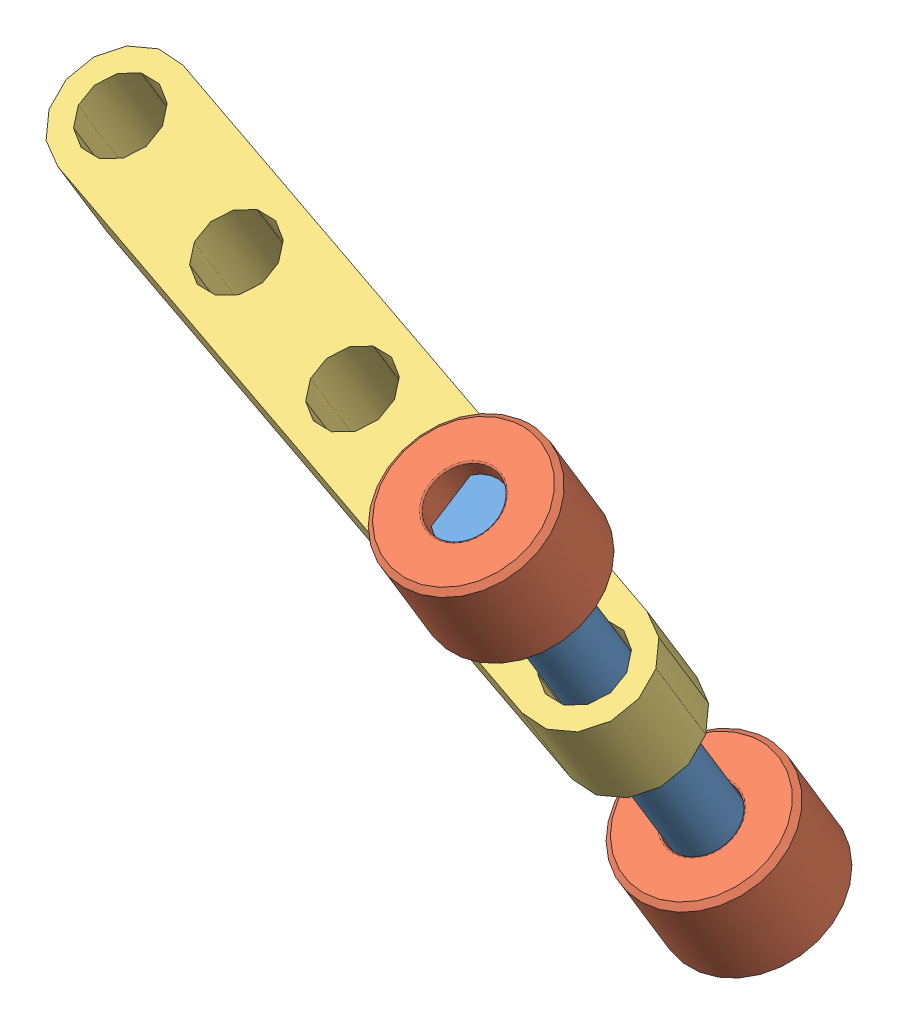
SolidWorks assembly Link Assembly - Upper Link Removed, configuration Default. Lengths in mm.
Overall size (35.69 26.34 20.92).
4 component instances, 3 part files, 28 mates.
Components (placement in the parent):
- Link D Shaft-1: Link D Shaft [Default] at (204.6422 -7.107 -10.2105) x (0 -0.854612 -0.519267) z (-0.011532 0.519233 -0.854555) size (25 2.4 2.9)
- 6056N11_Carbon Steel Set Screw Collar-5: 6056N11_Carbon Steel Set Screw Collar [6056N11] at (204.6422 -18.4789 -17.1202) x (-0.011532 0.519233 -0.854555) z (0 0.854612 0.519267) size (7 7.1 5)
- 6056N11_Carbon Steel Set Screw Collar-6: 6056N11_Carbon Steel Set Screw Collar [6056N11] at (204.6422 -0.0921 -5.9483) x (-0.011532 0.519233 -0.854555) z (0 0.854612 0.519267) size (7 7.1 5)
- Base Link-1: Base Link [Default] at (190.2189 -4.9679 -13.7311) x (-0.96155 0.142607 -0.234702) z (0 -0.854612 -0.519267) size (35.35 5.35 4.5)
Mates (geometry in assembly coordinates):
- Concentric30: concentric aligned: cylinder of Base Link v2-1 through (210.3071 -3.521 -6.1819) axis (0 -0.854612 -0.519267) radius 1.675; cylinder of Upper Link-1 through (199.4791 31.9793 -36.1428) axis (0 -0.854612 -0.519267) radius 1.51
- Coincident32: coincident aligned: plane of Base Link v2-1 through (196.7784 -8.808 -1.8135) normal (0 0.854612 0.519267); plane of Upper Link-1 through (206.0825 22.3111 -33.2299) normal (0 0.854612 0.519267)
- Coincident134: coincident aligned: plane of Base Link v2-1 through (196.7784 -8.808 -1.8135) normal (0 0.854612 0.519267); plane of Aluminum D Shaft-2 through (235.3041 1.5645 -21.6739) normal (0 0.854612 0.519267)
- Concentric78: concentric anti-aligned: cylinder of Aluminum D Shaft-2 through (235.3041 -5.2724 -25.828) axis (0 0.854612 0.519267) radius 1.45; cylinder of 6056N11_Carbon Steel Set Screw Collar-4 through (235.3041 18.9756 -11.0948) axis (0 -0.854612 -0.519267) radius 1.5
- Concentric79: concentric anti-aligned: cylinder of Aluminum D Shaft-2 through (235.3041 -5.2724 -25.828) axis (0 0.854612 0.519267) radius 1.45; cylinder of 6056N11_Carbon Steel Set Screw Collar-3 through (235.3041 7.9191 -17.8128) axis (0 -0.854612 -0.519267) radius 1.5
- Parallel31: parallel aligned: plane of Aluminum D Shaft-2 through (235.6236 -5.737 -25.0634) normal (0.336281 -0.489026 0.804841); plane of 6056N11_Carbon Steel Set Screw Collar-3 through (236.4811 4.0709 -16.294) normal (0.336281 -0.489026 0.804841)
- Parallel32: parallel aligned: plane of Aluminum D Shaft-2 through (235.6236 -5.737 -25.0634) normal (0.336281 -0.489026 0.804841); plane of 6056N11_Carbon Steel Set Screw Collar-4 through (236.4811 15.1275 -9.576) normal (0.336281 -0.489026 0.804841)
- Coincident178: coincident anti-aligned: plane of Upper Link-1 through (206.0825 22.3111 -33.2299) normal (0 0.854612 0.519267); plane of Link D Shaft-1 through (204.6422 -7.107 -10.2105) normal (0 -0.854612 -0.519267)
- Concentric113: concentric anti-aligned: cylinder of Upper Link-1 through (199.4791 20.4421 -43.1529) axis (0 0.854612 0.519267) radius 1.51; cylinder of Link D Shaft-1 through (204.6422 3.5757 -3.7197) axis (0 -0.854612 -0.519267) radius 1.45
- Concentric114: concentric aligned: cylinder of Link D Shaft-1 through (204.6422 3.5757 -3.7197) axis (0 -0.854612 -0.519267) radius 1.45; cylinder of 6056N11_Carbon Steel Set Screw Collar-5 through (204.6422 -14.2059 -14.5239) axis (0 -0.854612 -0.519267) radius 1.5
- Parallel33: parallel aligned: plane of Link D Shaft-1 through (203.6922 3.57 -3.7103) normal (-0.999934 -0.005988 0.009855); plane of 6056N11_Carbon Steel Set Screw Collar-5 through (201.1424 -16.3634 -15.7875) normal (-0.999934 -0.005988 0.009855)
- Concentric115: concentric aligned: cylinder of Link D Shaft-1 through (204.6422 3.5757 -3.7197) axis (0 -0.854612 -0.519267) radius 1.45; cylinder of 6056N11_Carbon Steel Set Screw Collar-6 through (204.6422 4.1809 -3.3519) axis (0 -0.854612 -0.519267) radius 1.5
- Parallel34: parallel aligned: plane of Link D Shaft-1 through (203.6922 3.57 -3.7103) normal (-0.999934 -0.005988 0.009855); plane of 6056N11_Carbon Steel Set Screw Collar-6 through (201.1424 2.0234 -4.6156) normal (-0.999934 -0.005988 0.009855)
- Coincident179: coincident anti-aligned: plane of Upper Link-1 through (206.0825 16.5425 -36.735) normal (0 -0.854612 -0.519267); plane of 6056N11_Carbon Steel Set Screw Collar-5 through (204.6422 -14.2059 -14.5239) normal (0 0.854612 0.519267)
- Coincident181: coincident anti-aligned: plane of Upper Link-1 through (206.0825 28.0798 -29.7249) normal (0 0.854612 0.519267); plane of 6056N11_Carbon Steel Set Screw Collar-6 through (204.6422 -0.0921 -5.9483) normal (0 -0.854612 -0.519267)
- Concentric130: concentric anti-aligned: cylinder of Link D Shaft-1 through (204.6422 3.5757 -3.7197) axis (0 -0.854612 -0.519267) radius 1.45; cylinder of Upper Link-2 through (214.1317 -11.1072 -13.8178) axis (0 0.854612 0.519267) radius 1.675
- Concentric131: concentric anti-aligned: cylinder of Aluminum D Shaft-2 through (235.3041 -5.2724 -25.828) axis (0 0.854612 0.519267) radius 1.45; cylinder of Upper Link-2 through (235.3041 3.4874 -20.5055) axis (0 -0.854612 -0.519267) radius 1.675
- Concentric132: concentric anti-aligned: cylinder of Base Link v2-1 through (210.3071 -3.521 -6.1819) axis (0 -0.854612 -0.519267) radius 1.675; cylinder of Upper Link-2 through (214.1317 -11.1072 -13.8178) axis (0 0.854612 0.519267) radius 1.675
- Coincident204: coincident anti-aligned: plane of 6056N11_Carbon Steel Set Screw Collar-5 through (204.6422 -14.2059 -14.5239) normal (0 0.854612 0.519267); plane of Upper Link-2 through (226.8352 -6.9654 -20.6345) normal (0 -0.854612 -0.519267)
- Coincident205: coincident anti-aligned: plane of 6056N11_Carbon Steel Set Screw Collar-6 through (204.6422 -0.0921 -5.9483) normal (0 -0.854612 -0.519267); plane of Upper Link-2 through (226.8352 4.5719 -13.6244) normal (0 0.854612 0.519267)
- Coincident206: coincident anti-aligned: plane of Link D Shaft-1 through (204.6422 -7.107 -10.2105) normal (0 -0.854612 -0.519267); plane of Upper Link-2 through (222.6007 -2.5773 -14.8572) normal (0 0.854612 0.519267)
- Coincident207: coincident aligned: plane of Base Link v2-1 through (196.7784 -8.808 -1.8135) normal (0 0.854612 0.519267); plane of Upper Link-2 through (222.6007 -2.5773 -14.8572) normal (0 0.854612 0.519267)
- Concentric133: concentric aligned: cylinder of Base Link v2-1 through (210.3071 -3.521 -6.1819) axis (0 -0.854612 -0.519267) radius 1.675; cylinder of Link D Shaft-1 through (204.6422 3.5757 -3.7197) axis (0 -0.854612 -0.519267) radius 1.45
- Coincident208: coincident anti-aligned: plane of Base Link v2-1 through (196.7784 -8.808 -1.8135) normal (0 0.854612 0.519267); plane of Link D Shaft-1 through (204.6422 -7.107 -10.2105) normal (0 -0.854612 -0.519267)
- Coincident209: coincident anti-aligned: plane of Base Link v2-1 through (184.405 -11.5022 6.9536) normal (0.431916 -0.468334 0.770786); plane of 9657K328_Compression Spring-1 through (186.6598 -12.8643 4.8624) normal (-0.431916 0.468334 -0.770786)
- Concentric134: concentric aligned: cylinder of Base Link v2-1 through (188.3875 -14.7377 7.9456) axis (-0.431916 0.468334 -0.770786) radius 2.4146; circle of 9657K328_Compression Spring-1
- Concentric145: concentric anti-aligned: cylinder of Link D Shaft-1 through (204.6422 3.5757 -3.7197) axis (0 -0.854612 -0.519267) radius 1.45; cylinder of Base Link-1 through (204.6422 -9.0299 -11.3789) axis (0 0.854612 0.519267) radius 1.675
- Coincident219: coincident aligned: plane of Link D Shaft-1 through (204.6422 -7.107 -10.2105) normal (0 -0.854612 -0.519267); plane of Base Link-1 through (190.2189 -4.9679 -13.7311) normal (0 -0.854612 -0.519267)
